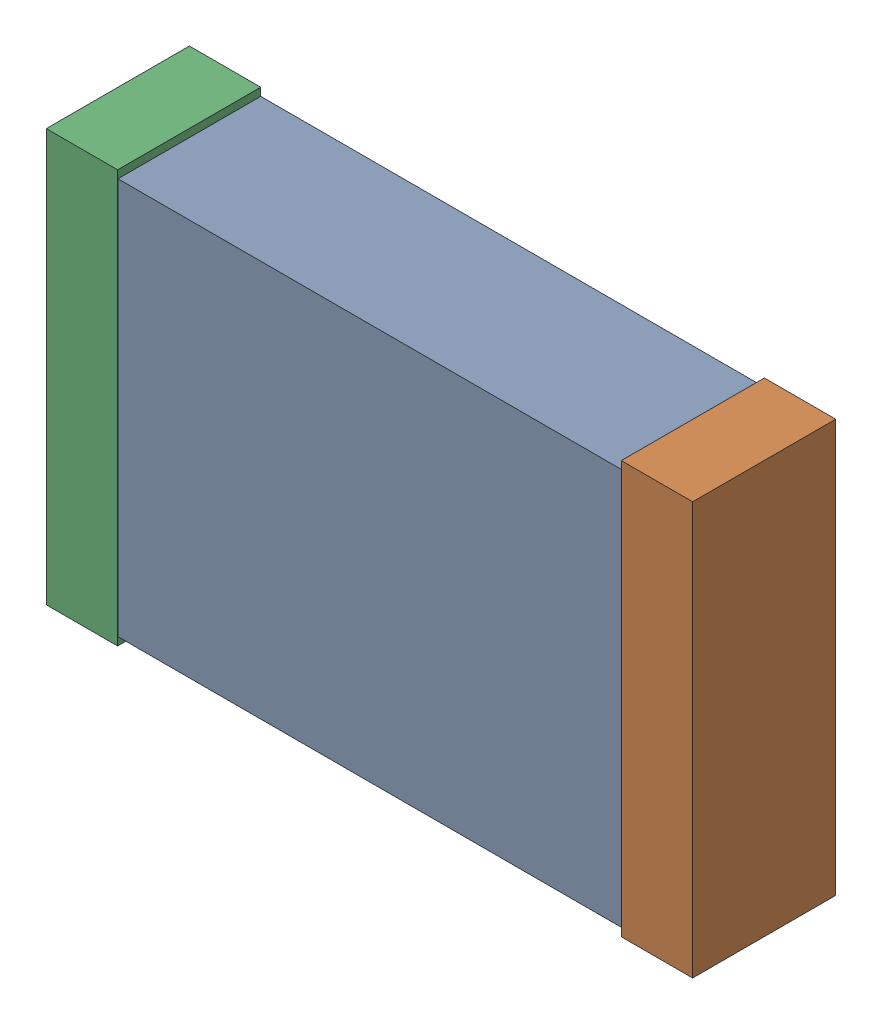
SolidWorks assembly C4, configuration Default. Lengths in mm.
Overall size (2.04 1.3 0.45).
6 component instances, 2 part files, 0 mates.
Components (placement in the parent):
- 870943200-1: 870943200 [Default] at (77.139 5.5604 0) size (2 1.25 0.45)
  - Extruded_39-1: Extruded_39 [Default] at origin size (2 1.25 0.45)
- 870943360-1: 870943360 [Default] at (78.0515 5.5604 0) size (0.23 1.3 0.45)
  - Extruded_40-1: Extruded_40 [Default] at origin size (0.23 1.3 0.45)
- 870943360-2: 870943360 [Default] at (76.239 5.5604 0) size (0.23 1.3 0.45)
  - Extruded_40-1: Extruded_40 [Default] at origin size (0.23 1.3 0.45)
